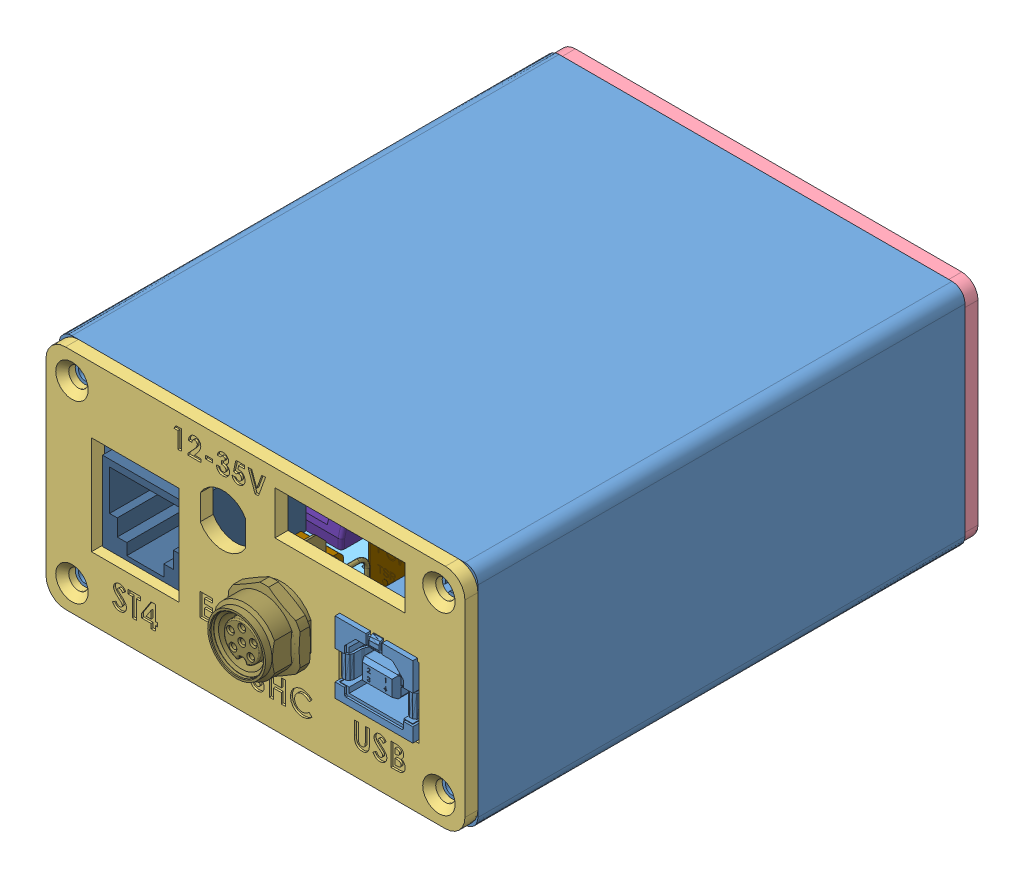
SolidWorks assembly 000 boitier full, configuration Default. Lengths in mm.
Overall size (70.8 51.64 92.8).
25 component instances, 19 part files, 9 mates.
Components (placement in the parent):
- 190 boitier tiny-1: 190 boitier tiny [Défaut] at origin size (64.5 35 75)
- 189 cyl7mm-1: 189 cyl7mm [Défaut] at (-17.3256 -8.5104 45.4808) x (1 0 0) z (0 1 0) size (8 8 11)
- 111 tiny-front-1: 111 tiny-front [Défaut] at (0 0 75) size (70.8 51.64 2)
- 112 tiny-back-1: 112 tiny-back [Défaut] x (-1 0 0) z (0 0 -1) size (64.5 35 2)
- tiny-1: tiny [Default] at (30 -8.5104 75) x (0 0 -1) z (0 1 0) size (92.8 60 28.45)
  - Board_tiny-1: Board_tiny [Default] at origin size (75 60 1.59)
  - clip_CR1620-1: clip_CR1620 [Default] at (24.987 11.8475 -1.5896) x (1 0 0) z (0 1 0) size (17.19 6.9 15.1)
  - cappr-2.54_5.08-1: cappr-2.54_5.08 [Default] at (32.7063 35.8775 -2.286) size (5.3 5.59 9.46)
  - D8x20coude-1: D8x20coude [Default] at (49.25 54 4.2) x (1 0 0) z (0 -1 0) size (7.87 11 23.4)
  - D8x20coude-2: D8x20coude [Default] at (49.25 30 4.2) x (1 0 0) z (0 -1 0) size (7.87 11 23.4)
  - diode_SMD_DO214_S5DC-13-F-1: diode_SMD_DO214_S5DC-13-F [Default] at (11.8988 37.1587 0) x (-1 0 0) z (0 0 1) size (7.94 5.9 2.5)
  - SS-90000-003-1: SS-90000-003 [Default] at (17.64 48.5 6.604) x (0 -1 0) z (-1 0 0) size (13.21 15.57 18.1)
  - RJE091884111A-1: RJE091884111A [Default] at (61.595 7.6 0) x (0 1 0) z (0 0 1) size (16.9 18.2 18.5)
  - M8_6pin_elbow_PCB-1: M8_6pin_elbow_PCB [Default] at (65.7 48 -2.413) x (0 1 0) z (0 0 1) size (12.8 20.4 15.35)
  - M8_6pin_elbow_PCB-2: M8_6pin_elbow_PCB [Default] at (65.7 30 -2.413) x (0 1 0) z (0 0 1) size (12.8 20.4 15.35)
  - M8_6pin_elbow_PCB-3: M8_6pin_elbow_PCB [Default] at (9.3 26 -2.413) x (0 -1 0) z (0 0 1) size (12.8 20.4 15.35)
  - Teensy_4.0_Assembly-1: Teensy_4.0_Assembly [Default] at (22.985 71.735 0) x (0 1 0) z (1 0 0) size (36.75 4.12 17.7)
  - TMC2130-V3.0-1: TMC2130-V3.0 [Default] at (49.25 44.2 9) x (1 0 0) z (0 -1 0) size (15.24 22.13 20.32)
  - TMC2130-V3.0-2: TMC2130-V3.0 [Default] at (49.25 20.2 9) x (1 0 0) z (0 -1 0) size (15.24 22.13 20.32)
  - sip-6_14.7x2x2.54-1: sip-6_14.7x2x2.54 [Default] at (27.305 37.8825 -2) x (0 1 0) z (0 0 1) size (14.8 2.16 7.95)
  - sip-8_21.6x2.4x2.54-1: sip-8_21.6x2.4x2.54 [Default] at (44.7675 7.4025 -2) x (-1 0 0) z (0 0 1) size (22.07 2.4 10.48)
  - sip-8_21.6x2.4x2.54-2: sip-8_21.6x2.4x2.54 [Default] at (44.7675 4.545 -2) x (-1 0 0) z (0 0 1) size (22.07 2.4 10.48)
  - suport_fusible_SMD-1: suport_fusible_SMD [Default] at (20.55 41.6825 0) x (1 0 0) z (0 -1 0) size (5.03 3.81 9.73)
  - TSR_1-2450-1: TSR_1-2450 [Default] at (19.1038 24.13 5.5) x (0 -1 0) z (-1 0 0) size (11.7 14.2 7.55)
  - 924-1: 924 [Default] at (8.8 11 0.2) x (0 -1 0) z (0 0 1) size (14.31 15.66 15.33)
Mates (geometry in assembly coordinates):
- Coïncidente1: coincident anti-aligned: plane of 190 boitier tiny-1 through (0 0 75) normal (0 0 1); plane of 111 tiny-front-1 through (0 0 75) normal (0 0 -1)
- Coïncidente2: coincident anti-aligned: plane of 190 boitier tiny-1 through (0 0 0) normal (0 0 -1); plane of 112 tiny-back-1 through (0 0 0) normal (0 0 1)
- Coïncidente3: coincident aligned: plane of 111 tiny-front-1 through (0 0 75) normal (0 1 0); plane of assembly through (0 0 0) normal (0 1 0)
- Coïncidente4: coincident aligned: plane of 111 tiny-front-1 through (0 0 75) normal (1 0 0); plane of assembly through (0 0 0) normal (1 0 0)
- Coïncidente5: coincident aligned: plane of 112 tiny-back-1 through (0 0 0) normal (0 1 0); plane of assembly through (0 0 0) normal (0 1 0)
- Coïncidente6: coincident anti-aligned: plane of 112 tiny-back-1 through (0 0 0) normal (-1 0 0); plane of assembly through (0 0 0) normal (1 0 0)
- Coincident11: coincident anti-aligned: plane of 190 boitier tiny-1 through (-30 -10.1 0) normal (0 1 0); plane of tiny-1/Board_tiny-1 through (30 -10.1 74) normal (0 -1 0)
- Symmetric2: symmetric aligned: plane of tiny-1/Board_tiny-1 through (-30 -8.5104 1) normal (-1 0 0); plane of tiny-1/Board_tiny-1 through (30 -8.5104 74) normal (1 0 0); plane of assembly through (0 0 0) normal (1 0 0)
- Coincident13: coincident: plane of 190 boitier tiny-1 through (0 0 75) normal (0 0 1); point of tiny-1/Board_tiny-1
